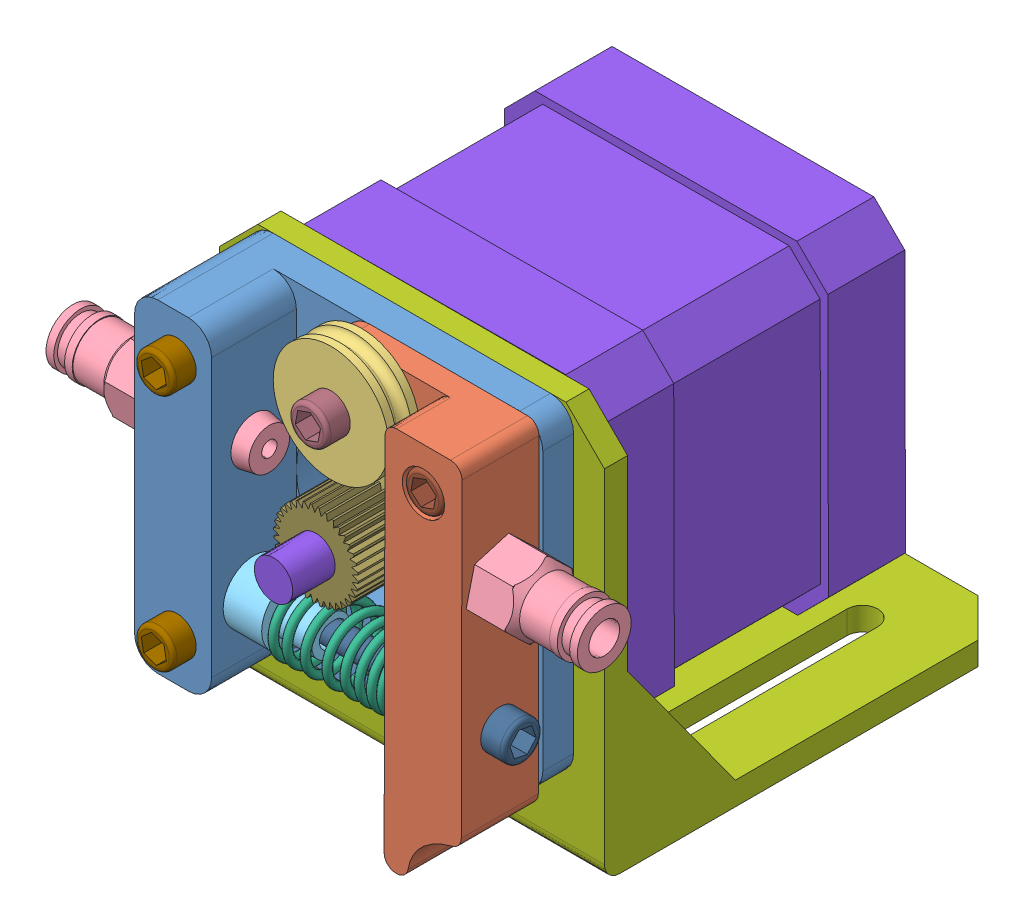
SolidWorks assembly Bowden Assembly, configuration Default. Lengths in mm.
Overall size (68.49 53.54 71.5).
16 component instances, 14 part files, 31 mates.
Components (placement in the parent):
- Main Block-1: Main Block [Default] at (16.5906 16.7583 27.7621) size (42 42 15)
- Arm-1: Arm [Default] at (32.0447 12.7584 31.7621) x (0.999997 -0.002353 0) z (0 0 1) size (25 50 10)
- Feed Bearing-1: Feed Bearing [Default] at (17.0906 32.2936 34.7621) size (15 15 4)
- PTFE 4mm Fitting-1: PTFE 4mm Fitting [Default] at (7.5906 22.7583 37.2621) x (0 0 1) z (-1 0 0) size (9.52 9.62 25.5)
- PTFE 4mm Fitting-2: PTFE 4mm Fitting [Default] at (25.0683 22.7748 36.7621) x (0 0 -1) z (0.999997 -0.002353 0) size (9.52 9.62 25.5)
- Adjust Mount-1: Adjust Mount [Default] at (5.5906 5.7583 37.2621) x (0 0 -1) z (1 0 0) size (8 8 10)
- Compression Spring-1: Compression Spring [Default] at (26.6918 6.1319 36.8921) x (-0.03687 0.954593 -0.295622) z (-0.999309 -0.03662 0.006384) size (9 9 16.75)
- Bowden LBracket-1: Bowden LBracket [Default] at (16.5906 -13.7417 1.0121) x (0 0 -1) z (0 1 0) size (53.5 50 51.5)
- Bowben Nema 17-1: Bowben Nema 17 [Default] at (16.6316 16.7994 -15.2379) x (0.999996 0.002653 0) z (0 0 1) size (42 42 61)
- Hex M3x22-5: Hex M3x22 [Default] at (1.0906 1.2583 45.7621) x (0.230478 -0.973077 0) z (0 0 -1) size (5 5 25)
- Hex M3x22-7: Hex M3x22 [Default] at (1.0906 32.2583 45.7621) x (0.230478 -0.973077 0) z (0 0 -1) size (5 5 25)
- Hex M3x25-1: Hex M3x25 [Default] at (40.0282 5.7396 36.7621) x (0.002187 0.92966 0.368411) z (-0.999997 0.002353 0) size (5 5 28)
- Hex M3x20-3: Hex M3x20 [Default] at (32.0906 32.2583 41.7621) x (-0.923728 -0.383049 0) z (0 0 -1) size (5 5 23)
- Toothed Filament Feed-1: Toothed Filament Feed [Default] at (16.6316 16.7994 40.2533) x (-0.928407 -0.371565 0) z (0 0 -1) size (10.98 10.98 11)
- Hex M3x6-1: Hex M3x6 [Default] at (17.0906 32.2936 41.7621) x (-0.923728 -0.383049 0) z (0 0 -1) size (5 5 9)
- Hex M3x15-1: Hex M3x15 [Default] at (-7.4094 5.7583 37.2621) x (0 -0.924225 -0.381849) z (1 0 0) size (5 5 18)
Mates (geometry in assembly coordinates):
- Concentric1: concentric aligned: cylinder of Main Block-1 through (32.0906 32.2583 21.7621) axis (0 0 1) radius 1.75; cylinder of Arm-1 through (32.0906 32.2583 31.7621) axis (0 0 1) radius 1.75
- Coincident1: coincident anti-aligned: plane of Main Block-1 through (16.5906 16.7583 31.7621) normal (0 0 1); plane of Arm-1 through (32.0447 12.7584 31.7621) normal (0 0 -1)
- Concentric2: concentric aligned: cylinder of Arm-1 through (17.0906 32.2936 19.7621) axis (0 0 1) radius 1.35; cylinder of Feed Bearing-1 through (17.0906 32.2936 33.7621) axis (0 0 1) radius 1.5
- Coincident2: coincident anti-aligned: plane of Arm-1 through (12.1036 37.8054 34.7621) normal (0 0 1); plane of Feed Bearing-1 through (17.0906 32.2936 34.7621) normal (0 0 -1)
- Concentric3: concentric anti-aligned: cylinder of Main Block-1 through (16.5906 22.7583 37.2621) axis (-1 0 0) radius 3; cylinder of PTFE 4mm Fitting-1 through (-4.4094 22.7583 37.2621) axis (1 0 0) radius 3
- Coincident3: coincident anti-aligned: plane of Main Block-1 through (-4.4094 37.7583 31.7621) normal (-1 0 0); plane of PTFE 4mm Fitting-1 through (-4.4094 22.7583 37.2621) normal (1 0 0)
- Concentric4: concentric anti-aligned: cylinder of Arm-1 through (24.0683 22.7772 36.7621) axis (0.999997 -0.002353 0) radius 3; cylinder of PTFE 4mm Fitting-2 through (37.0682 22.7466 36.7621) axis (-0.999997 0.002353 0) radius 3
- Coincident4: coincident anti-aligned: plane of Arm-1 through (37.1035 37.7465 41.7621) normal (0.999997 -0.002353 0); plane of PTFE 4mm Fitting-2 through (37.0682 22.7466 36.7621) normal (-0.999997 0.002353 0)
- Coincident5: coincident anti-aligned: plane of Main Block-1 through (5.5906 37.7583 42.7621) normal (1 0 0); plane of Adjust Mount-1 through (5.5906 5.7583 37.2621) normal (-1 0 0)
- Coincident6: coincident anti-aligned: plane of Main Block-1 through (5.5906 37.7583 42.7621) normal (1 0 0); plane of Adjust Mount-1 through (5.5906 5.7583 37.2621) normal (-1 0 0)
- Concentric5: concentric aligned: cylinder of Main Block-1 through (16.5906 5.7583 37.2621) axis (-1 0 0) radius 1.5; cylinder of Adjust Mount-1 through (15.5906 5.7583 37.2621) axis (-1 0 0) radius 1.5
- Concentric6: concentric aligned: cylinder of Main Block-1 through (1.0906 32.2583 21.7621) axis (0 0 1) radius 1.75; cylinder of Bowden LBracket-1 through (1.0906 32.2583 17.7621) axis (0 0 1) radius 1.75
- Concentric7: concentric aligned: cylinder of Main Block-1 through (32.0906 32.2583 21.7621) axis (0 0 1) radius 1.75; cylinder of Bowden LBracket-1 through (32.0906 32.2583 17.7621) axis (0 0 1) radius 1.75
- Coincident9: coincident anti-aligned: plane of Main Block-1 through (16.5906 16.7583 42.7621) normal (0 0 1); plane of ? through (1.0906 32.2583 42.7621) normal (0 0 -1)
- Concentric10: concentric aligned: cylinder of Main Block-1 through (1.0906 32.2583 21.7621) axis (0 0 1) radius 1.75; cylinder of ? through (1.0906 32.2583 20.7621) axis (0 0 1) radius 1.5
- Coincident10: coincident anti-aligned: plane of Main Block-1 through (16.5906 16.7583 42.7621) normal (0 0 1); plane of Hex M3x22-5 through (1.0906 1.2583 42.7621) normal (0 0 -1)
- Concentric11: concentric aligned: cylinder of Main Block-1 through (1.0906 1.2583 21.7621) axis (0 0 1) radius 1.75; cylinder of Hex M3x22-5 through (1.0906 1.2583 20.7621) axis (0 0 1) radius 1.5
- Concentric12: concentric aligned: cylinder of Main Block-1 through (1.0906 32.2583 21.7621) axis (0 0 1) radius 1.75; cylinder of Hex M3x22-7 through (1.0906 32.2583 20.7621) axis (0 0 1) radius 1.5
- Coincident11: coincident anti-aligned: plane of Main Block-1 through (16.5906 16.7583 42.7621) normal (0 0 1); plane of Hex M3x22-7 through (1.0906 32.2583 42.7621) normal (0 0 -1)
- Coincident12: coincident anti-aligned: plane of Arm-1 through (32.0906 32.2583 38.7621) normal (0 0 1); plane of Hex M3x20-3 through (32.0906 32.2583 38.7621) normal (0 0 -1)
- Concentric13: concentric aligned: cylinder of Arm-1 through (32.0906 32.2583 31.7621) axis (0 0 1) radius 1.75; cylinder of Hex M3x20-3 through (32.0906 32.2583 13.7621) axis (0 0 1) radius 1.5
- Concentric14: concentric: cylinder of Arm-1 through (22.0223 5.7842 36.7621) axis (0.999997 -0.002579 0) radius 1.5; cylinder of ? through (17.0223 5.7971 36.7621) axis (0.999997 -0.002579 0) radius 1.5
- Coincident13: coincident anti-aligned: plane of Arm-1; plane of ? through (37.0222 5.7455 36.7621) normal (-0.999997 0.002579 0)
- Concentric15: concentric aligned: cylinder of Arm-1 through (22.0283 5.7819 36.7621) axis (0.999997 -0.002353 0) radius 1.5; cylinder of Hex M3x25-1 through (12.0283 5.8054 36.7621) axis (0.999997 -0.002353 0) radius 1.5
- Coincident14: coincident anti-aligned: plane of Arm-1 through (37.1035 37.7465 41.7621) normal (0.999997 -0.002353 0); plane of Hex M3x25-1 through (37.0282 5.7466 36.7621) normal (-0.999997 0.002353 0)
- Coincident15: coincident anti-aligned: plane of Arm-1 through (32.0906 32.2583 38.7621) normal (0 0 1); plane of Hex M3x20-3 through (32.0906 32.2583 38.7621) normal (0 0 -1)
- Concentric16: concentric aligned: cylinder of Arm-1 through (32.0906 32.2583 31.7621) axis (0 0 1) radius 1.75; cylinder of Hex M3x20-3 through (32.0906 32.2583 18.7621) axis (0 0 1) radius 1.5
- Concentric18: concentric aligned: cylinder of Feed Bearing-1 through (17.0906 32.2936 33.7621) axis (0 0 1) radius 1.5; cylinder of Hex M3x6-1 through (17.0906 32.2936 32.7621) axis (0 0 1) radius 1.5
- Coincident16: coincident anti-aligned: plane of Feed Bearing-1 through (17.0906 32.2936 38.7621) normal (0 0 1); plane of Hex M3x6-1 through (17.0906 32.2936 38.7621) normal (0 0 -1)
- Concentric19: concentric aligned: cylinder of Main Block-1 through (16.5906 5.7583 37.2621) axis (-1 0 0) radius 1.5; cylinder of Hex M3x15-1 through (10.5906 5.7583 37.2621) axis (-1 0 0) radius 1.5
- Coincident17: coincident anti-aligned: plane of Main Block-1 through (-4.4094 37.7583 31.7621) normal (-1 0 0); plane of Hex M3x15-1 through (-4.4094 5.7583 37.2621) normal (1 0 0)
